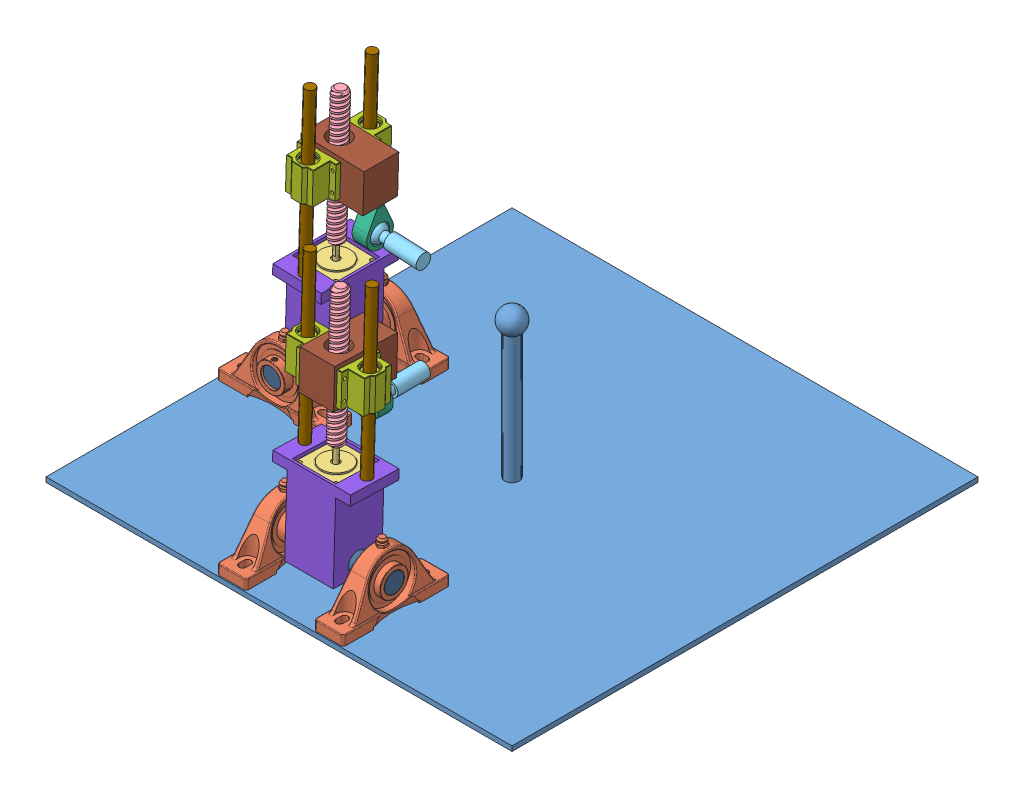
SolidWorks assembly vertical_Assem rev3, configuration Default. Lengths in mm.
Overall size (609.6 357.31 609.6).
28 component instances, 12 part files, 76 mates.
Components (placement in the parent):
- Bottom Platform rev2-1: Bottom Platform rev2 [Default] at origin size (609.6 200.03 609.6)
- 7728T560_MOUNTED BALL BEARING WITH CAST IRON HOUSING-1: 7728T560_MOUNTED BALL BEARING WITH CAST IRON HOUSING [7728T56] at (-63.5 42.8625 233.3625) x (0 0 -1) z (1 0 0) size (139.7 80.96 38.1)
- 7728T560_MOUNTED BALL BEARING WITH CAST IRON HOUSING-2: 7728T560_MOUNTED BALL BEARING WITH CAST IRON HOUSING [7728T56] at (-233.3625 42.8625 63.5) size (139.7 80.96 38.1)
- 7728T560_MOUNTED BALL BEARING WITH CAST IRON HOUSING-3: 7728T560_MOUNTED BALL BEARING WITH CAST IRON HOUSING [7728T56] at (-233.3625 42.8625 -63.5) size (139.7 80.96 38.1)
- 7728T560_MOUNTED BALL BEARING WITH CAST IRON HOUSING-4: 7728T560_MOUNTED BALL BEARING WITH CAST IRON HOUSING [7728T56] at (63.5 42.8625 233.3625) x (0 0 1) z (-1 0 0) size (139.7 80.96 38.1)
- 6627T540_POSITION-CONTROL DC MOTOR-2: 6627T540_POSITION-CONTROL DC MOTOR [6627T54] at (0 137.4326 230.4477) x (1 0 0) z (0 0.999525 -0.030807) size (57.15 58.17 99.31)
- 6627T540_POSITION-CONTROL DC MOTOR-3: 6627T540_POSITION-CONTROL DC MOTOR [6627T54] at (-230.4293 137.432 0) x (0 0 -1) z (0.031002 0.999519 0) size (57.15 58.17 99.31)
- 5966K221_BALL SCREW-3: 5966K221_BALL SCREW [5966K221] at (-229.7914 157.9961 0) x (0.970979 -0.030116 -0.237261) z (-0.031002 -0.999519 0) size (20.38 19.09 183.37)
- 5966K221_BALL SCREW-4: 5966K221_BALL SCREW [5966K221] at (0 157.9968 229.8138) x (0.271467 0.029651 0.961991) z (0 -0.999525 0.030807) size (20.38 19.09 183.37)
- top_Platform rev2-1: top_Platform rev2 [Default] at (0.7095 200.0079 0.2014) x (-0.999001 0.044698 -0.000225) z (-0.000791 -0.012664 0.999919) size (317.5 25.4 317.5) (hidden)
- ball-2: ball [Default] at (0.0499 185.85 116.2359) x (0.999641 -0.0268 0.000452) z (-0.026792 -0.999561 -0.01268) size (25.4 75.77 25.4)
- hole-1: hole [Default] at (0 258.8925 180.1999) x (0 0.030807 0.999525) z (1 0 0) size (19.05 91.29 35.03)
- ball-3: ball [Default] at (-115.947 192.5157 0.0142) x (0.040283 0.898119 -0.437904) z (0.019372 0.437476 0.899022) size (25.4 75.77 25.4)
- hole-2: hole [Default] at (-179.8387 269.1761 0) x (-0.999519 0.031002 0) z (0 0 1) size (19.05 91.29 35.03)
- 9338T100_MOUNTED LINEAR BALL BRNG-1: 9338T100_MOUNTED LINEAR BALL BRNG [9338T1] at (39.0525 243.1877 227.1881) x (0 -0.030807 -0.999525) z (0 0.999525 -0.030807) size (50.8 31.75 42.86)
- 9338T100_MOUNTED LINEAR BALL BRNG-2: 9338T100_MOUNTED LINEAR BALL BRNG [9338T1] at (-39.116 243.1887 227.2198) x (0 0.030807 0.999525) z (0 0.999525 -0.030807) size (50.8 31.75 42.86)
- 9338T100_MOUNTED LINEAR BALL BRNG-3: 9338T100_MOUNTED LINEAR BALL BRNG [9338T1] at (-226.8616 253.4814 -39.116) x (-0.999519 0.031002 0) z (0.031002 0.999519 0) size (50.8 31.75 42.86)
- 9338T100_MOUNTED LINEAR BALL BRNG-4: 9338T100_MOUNTED LINEAR BALL BRNG [9338T1] at (-226.8298 253.4804 39.0525) x (0.999519 -0.031002 0) z (0.031002 0.999519 0) size (50.8 31.75 42.86)
- motor mount-2: motor mount [Default] at (-265.5894 27.9794 -31.75) x (0 0 1) z (-0.999519 0.031002 0) size (101.6 114.3 63.5)
- motor mount-3: motor mount [Default] at (-31.75 27.9732 265.5865) x (1 0 0) z (0 0.030807 0.999525) size (101.6 114.3 63.5)
- linear bar-1: linear bar [Default] at (-230.8615 128.5512 -40.64) x (0.999519 -0.031002 0.000002) z (-0.000002 0 1) size (12.7 228.6 12.7)
- linear bar-2: linear bar [Default] at (40.64 128.5468 230.7215) x (-0.564697 -0.025425 -0.824906) z (0.825298 -0.017397 -0.564429) size (12.7 228.6 12.7)
- linear bar-3: linear bar [Default] at (-40.64 128.5516 230.8782) x (-0.912321 -0.012615 -0.409281) z (0.409475 -0.028106 -0.911888) size (12.7 228.6 12.7)
- linear bar-4: linear bar [Default] at (-230.7049 128.5463 40.64) x (0.951171 -0.029502 0.307253) z (-0.307105 0.009525 0.951628) size (12.7 228.6 12.7)
- horizontal bar-1: horizontal bar [Default] at (-79.375 42.8625 233.3625) size (158.75 25.4 25.4)
- horizontal bar-2: horizontal bar [Default] at (-233.3625 42.8625 -79.375) x (0 0 1) z (-1 0 0) size (158.75 25.4 25.4)
- screw_attach rev3-1: screw_attach rev3 [Default] at (-255.4169 228.9549 -23.241) x (0.999519 -0.031002 0) z (0 0 1) size (82.55 50.8 45.47)
- screw_attach rev3-2: screw_attach rev3 [Default] at (-23.241 218.6566 255.7704) x (0 -0.030807 -0.999525) z (1 0 0) size (82.55 50.8 45.47)
Mates (geometry in assembly coordinates):
- Coincident1: coincident anti-aligned: plane of Bottom Platform rev2-1 through (0 6.35 0) normal (0 1 0); plane of 7728T560_MOUNTED BALL BEARING WITH CAST IRON HOUSING-1 through (-44.45 6.35 203.2) normal (0 -1 0)
- Tangent3: tangent anti-aligned: cylinder of Bottom Platform rev2-1 through (-63.5 6.35 180.975) axis (0 1 0) radius 4.7625; plane of 7728T560_MOUNTED BALL BEARING WITH CAST IRON HOUSING-1 through (-58.7375 6.35 288.925) normal (-1 0 0)
- Tangent5: tangent anti-aligned: cylinder of Bottom Platform rev2-1 through (-63.5 6.35 285.75) axis (0 1 0) radius 4.7625; plane of 7728T560_MOUNTED BALL BEARING WITH CAST IRON HOUSING-1 through (-58.7375 6.35 288.925) normal (-1 0 0)
- Coincident3: coincident: cylinder of Bottom Platform rev2-1 through (-63.5 6.35 180.975) axis (0 1 0) radius 4.7625; moEndPointRef_w of 7728T560_MOUNTED BALL BEARING WITH CAST IRON HOUSING-1
- Coincident4: coincident anti-aligned: plane of Bottom Platform rev2-1 through (0 6.35 0) normal (0 1 0); plane of 7728T560_MOUNTED BALL BEARING WITH CAST IRON HOUSING-2 through (-303.2125 6.35 82.55) normal (0 -1 0)
- Coincident5: coincident anti-aligned: plane of Bottom Platform rev2-1 through (0 6.35 0) normal (0 1 0); plane of 7728T560_MOUNTED BALL BEARING WITH CAST IRON HOUSING-4 through (44.45 6.35 163.5125) normal (0 -1 0)
- Coincident6: coincident anti-aligned: plane of Bottom Platform rev2-1 through (0 6.35 0) normal (0 1 0); plane of 7728T560_MOUNTED BALL BEARING WITH CAST IRON HOUSING-3 through (-303.2125 6.35 -44.45) normal (0 -1 0)
- Tangent6: tangent anti-aligned: cylinder of Bottom Platform rev2-1 through (63.5 6.35 285.75) axis (0 1 0) radius 4.7625; plane of 7728T560_MOUNTED BALL BEARING WITH CAST IRON HOUSING-4 through (68.2625 6.35 282.575) normal (-1 0 0)
- Tangent7: tangent anti-aligned: cylinder of Bottom Platform rev2-1 through (63.5 6.35 180.975) axis (0 1 0) radius 4.7625; plane of 7728T560_MOUNTED BALL BEARING WITH CAST IRON HOUSING-4 through (68.2625 6.35 177.8) normal (-1 0 0)
- Coincident7: coincident: cylinder of Bottom Platform rev2-1 through (63.5 6.35 180.975) axis (0 1 0) radius 4.7625; moEndPointRef_w of 7728T560_MOUNTED BALL BEARING WITH CAST IRON HOUSING-4
- Tangent8: tangent anti-aligned: cylinder of Bottom Platform rev2-1 through (-180.975 6.35 63.5) axis (0 1 0) radius 4.7625; plane of 7728T560_MOUNTED BALL BEARING WITH CAST IRON HOUSING-2 through (-184.15 6.35 58.7375) normal (0 0 1)
- Tangent9: tangent anti-aligned: cylinder of Bottom Platform rev2-1 through (-285.75 6.35 63.5) axis (0 1 0) radius 4.7625; plane of 7728T560_MOUNTED BALL BEARING WITH CAST IRON HOUSING-2 through (-288.925 6.35 58.7375) normal (0 0 1)
- Coincident8: coincident: cylinder of Bottom Platform rev2-1 through (-180.975 6.35 63.5) axis (0 1 0) radius 4.7625; moEndPointRef_w of 7728T560_MOUNTED BALL BEARING WITH CAST IRON HOUSING-2
- Tangent10: tangent anti-aligned: cylinder of Bottom Platform rev2-1 through (-180.975 6.35 -63.5) axis (0 1 0) radius 4.7625; plane of 7728T560_MOUNTED BALL BEARING WITH CAST IRON HOUSING-3 through (-184.15 6.35 -68.2625) normal (0 0 1)
- Tangent11: tangent anti-aligned: cylinder of Bottom Platform rev2-1 through (-285.75 6.35 -63.5) axis (0 1 0) radius 4.7625; plane of 7728T560_MOUNTED BALL BEARING WITH CAST IRON HOUSING-3 through (-288.925 6.35 -68.2625) normal (0 0 1)
- Coincident9: coincident: cylinder of Bottom Platform rev2-1 through (-285.75 6.35 -63.5) axis (0 1 0) radius 4.7625; moEndPointRef_w of 7728T560_MOUNTED BALL BEARING WITH CAST IRON HOUSING-3
- Coincident12: coincident: moEndPointRef_w of 6627T540_POSITION-CONTROL DC MOTOR-3; plane of assembly
- Coincident13: coincident: moEndPointRef_w of 6627T540_POSITION-CONTROL DC MOTOR-2; plane of assembly
- Coincident16: coincident anti-aligned: plane of 6627T540_POSITION-CONTROL DC MOTOR-3 through (-232.9649 158.0946 0) normal (0.031002 0.999519 0); plane of 5966K221_BALL SCREW-3 through (-229.7914 157.9961 0) normal (-0.031002 -0.999519 0)
- Concentric5: concentric anti-aligned: cylinder of 6627T540_POSITION-CONTROL DC MOTOR-3 through (-229.7914 157.9961 0) axis (0.031002 0.999519 0) radius 3.175; cylinder of 5966K221_BALL SCREW-3 through (-224.2793 335.7107 0) axis (-0.031002 -0.999519 0) radius 9.525
- Concentric6: concentric anti-aligned: cylinder of 6627T540_POSITION-CONTROL DC MOTOR-2 through (0 157.9968 229.8138) axis (0 0.999525 -0.030807) radius 3.175; cylinder of 5966K221_BALL SCREW-4 through (0 335.7124 224.3363) axis (0 -0.999525 0.030807) radius 9.525
- Coincident17: coincident anti-aligned: plane of 6627T540_POSITION-CONTROL DC MOTOR-2 through (0 157.899 226.6403) normal (0 0.999525 -0.030807); plane of 5966K221_BALL SCREW-4 through (0 157.9968 229.8138) normal (0 -0.999525 0.030807)
- Concentric18: concentric anti-aligned: cylinder of top_Platform rev2-1 through (0.0162 185.3112 158.7775) axis (-0.000791 -0.012664 0.999919) radius 9.525; cylinder of ball-2 through (0.0162 185.3112 158.7775) axis (0.000791 0.012664 -0.999919) radius 9.525
- Coincident31: coincident aligned: circle of top_Platform rev2-1; circle of ball-2
- Tangent12: tangent aligned: sphere of ball-2; cylinder of hole-1 through (0 184.8557 172.9524) axis (0 0.030807 0.999525) radius 12.7
- Concentric20: concentric anti-aligned: cylinder of top_Platform rev2-1 through (-158.4494 194.4173 0.0046) axis (-0.999001 0.044698 -0.000225) radius 9.525; cylinder of ball-3 through (-158.4494 194.4173 0.0046) axis (0.999001 -0.044698 0.000225) radius 9.525
- Coincident35: coincident aligned: plane of top_Platform rev2-1 through (-159.1427 179.7207 158.5807) normal (-0.999001 0.044698 -0.000225); plane of ball-3 through (-158.4494 194.4173 0.0046) normal (-0.999001 0.044698 -0.000225)
- Tangent13: tangent aligned: sphere of ball-3; cylinder of hole-2 through (-172.6055 195.1378 0) axis (-0.999519 0.031002 0) radius 12.7
- Parallel5: parallel anti-aligned: plane of Bottom Platform rev2-1 through (0 6.35 0) normal (0 1 0); plane of top_Platform rev2-1
- Tangent16: tangent aligned: sphere of Bottom Platform rev2-1; cylinder of top_Platform rev2-1 through (-0.4257 174.6353 -0.1208) axis (0.044691 0.99892 0.012687) radius 15.875
- Tangent18: tangent aligned: sphere of Bottom Platform rev2-1; plane of top_Platform rev2-1 through (0.7095 200.0079 0.2014) normal (0.044691 0.99892 0.012687)
- Coincident50: coincident anti-aligned: plane of 6627T540_POSITION-CONTROL DC MOTOR-3 through (-217.79 58.2621 25.019) normal (-0.031002 -0.999519 0); plane of motor mount-2 through (-264.6051 59.7142 -31.75) normal (0.031002 0.999519 0)
- Coincident51: coincident anti-aligned: plane of 6627T540_POSITION-CONTROL DC MOTOR-3 through (-205.199 131.567 -28.575) normal (0 0 -1); plane of motor mount-2 through (-258.8724 142.1261 -28.575) normal (0 0 1)
- Coincident52: coincident anti-aligned: plane of 6627T540_POSITION-CONTROL DC MOTOR-3 through (-259.148 133.2403 -25.4) normal (-0.999519 0.031002 0); plane of motor mount-2 through (-258.8724 142.1261 -28.575) normal (0.999519 -0.031002 0)
- Coincident53: coincident anti-aligned: plane of 6627T540_POSITION-CONTROL DC MOTOR-2 through (-25.019 59.1948 247.9539) normal (0 -0.999525 0.030807); plane of motor mount-3 through (-31.75 59.7081 264.6084) normal (0 0.999525 -0.030807)
- Coincident54: coincident anti-aligned: plane of 6627T540_POSITION-CONTROL DC MOTOR-2 through (25.4 131.4747 202.0427) normal (0 -0.030807 -0.999525); plane of motor mount-3 through (-28.575 140.3605 201.7688) normal (0 0.030807 0.999525)
- Coincident55: coincident anti-aligned: plane of 6627T540_POSITION-CONTROL DC MOTOR-2 through (28.575 133.1375 255.9921) normal (1 0 0); plane of motor mount-3 through (28.575 142.1211 258.8917) normal (-1 0 0)
- Coincident56: coincident aligned: plane of motor mount-2 through (-262.4396 129.5306 -50.8) normal (-0.031002 -0.999519 0); plane of linear bar-1 through (-230.8615 128.5512 -40.64) normal (-0.031002 -0.999519 0)
- Concentric43: concentric anti-aligned: cylinder of motor mount-2 through (-230.4678 141.245 -40.64) axis (0.031002 0.999519 0) radius 6.35; cylinder of linear bar-1 through (-223.7745 357.0413 -40.64) axis (-0.031002 -0.999519 0) radius 6.35
- Concentric44: concentric anti-aligned: cylinder of motor mount-2 through (-230.3112 141.2402 40.64) axis (0.031002 0.999519 0) radius 6.35; cylinder of linear bar-4 through (-223.6179 357.0364 40.64) axis (-0.031002 -0.999519 0) radius 6.35
- Coincident57: coincident aligned: plane of motor mount-2 through (-262.4396 129.5306 50.8) normal (-0.031002 -0.999519 0); plane of linear bar-4 through (-230.7049 128.5463 40.64) normal (-0.031002 -0.999519 0)
- Concentric45: concentric anti-aligned: cylinder of motor mount-3 through (-40.64 141.2456 230.4869) axis (0 0.999525 -0.030807) radius 6.35; cylinder of linear bar-3 through (-40.64 357.0431 223.8356) axis (0 -0.999525 0.030807) radius 6.35
- Concentric46: concentric anti-aligned: cylinder of motor mount-3 through (40.64 141.2408 230.3303) axis (0 0.999525 -0.030807) radius 6.35; cylinder of linear bar-2 through (40.64 357.0383 223.679) axis (0 -0.999525 0.030807) radius 6.35
- Coincident58: coincident aligned: plane of motor mount-3 through (-50.8 129.5249 262.4565) normal (0 -0.999525 0.030807); plane of linear bar-3 through (-40.64 128.5516 230.8782) normal (0 -0.999525 0.030807)
- Coincident59: coincident aligned: plane of motor mount-3 through (50.8 129.5249 262.4565) normal (0 -0.999525 0.030807); plane of linear bar-2 through (40.64 128.5468 230.7215) normal (0 -0.999525 0.030807)
- Concentric47: concentric anti-aligned: cylinder of 9338T100_MOUNTED LINEAR BALL BRNG-1 through (40.64 221.7666 227.8483) axis (0 0.999525 -0.030807) radius 6.35; cylinder of linear bar-2 through (40.64 357.0383 223.679) axis (0 -0.999525 0.030807) radius 6.35
- Concentric48: concentric anti-aligned: cylinder of 9338T100_MOUNTED LINEAR BALL BRNG-4 through (-227.4943 232.0594 40.64) axis (0.031002 0.999519 0) radius 6.35; cylinder of linear bar-4 through (-223.6179 357.0364 40.64) axis (-0.031002 -0.999519 0) radius 6.35
- Coincident60: coincident aligned: plane of 7728T560_MOUNTED BALL BEARING WITH CAST IRON HOUSING-1 through (-79.375 42.8625 233.3625) normal (-1 0 0); plane of horizontal bar-1 through (-79.375 42.8625 233.3625) normal (-1 0 0)
- Concentric51: concentric anti-aligned: cylinder of 7728T560_MOUNTED BALL BEARING WITH CAST IRON HOUSING-1 through (-79.375 42.8625 233.3625) axis (1 0 0) radius 12.7025; cylinder of horizontal bar-1 through (79.375 42.8625 233.3625) axis (-1 0 0) radius 12.7
- Coincident61: coincident aligned: plane of 7728T560_MOUNTED BALL BEARING WITH CAST IRON HOUSING-3 through (-233.3625 42.8625 -79.375) normal (0 0 -1); plane of horizontal bar-2 through (-233.3625 42.8625 -79.375) normal (0 0 -1)
- Concentric52: concentric anti-aligned: cylinder of 7728T560_MOUNTED BALL BEARING WITH CAST IRON HOUSING-3 through (-233.3625 42.8625 -79.375) axis (0 0 1) radius 12.7025; cylinder of horizontal bar-2 through (-233.3625 42.8625 79.375) axis (0 0 -1) radius 12.7
- Concentric54: concentric anti-aligned: cylinder of motor mount-2 through (-233.3625 42.8625 31.75) axis (0 0 1) radius 12.7; cylinder of horizontal bar-2 through (-233.3625 42.8625 79.375) axis (0 0 -1) radius 12.7
- Concentric56: concentric anti-aligned: cylinder of motor mount-3 through (31.75 42.8625 233.3625) axis (1 0 0) radius 12.7; cylinder of horizontal bar-1 through (79.375 42.8625 233.3625) axis (-1 0 0) radius 12.7
- Screw1: screw = 25.4 mm anti-aligned: cylinder of 5966K221_BALL SCREW-3 through (-224.2793 335.7107 0) axis (-0.031002 -0.999519 0) radius 9.525; cylinder of screw_attach rev3-1 through (-227.6173 228.0926 0) axis (0.031002 0.999519 0) radius 14
- Coincident62: coincident anti-aligned: plane of 9338T100_MOUNTED LINEAR BALL BRNG-3 through (-200.8094 274.1149 -23.241) normal (0 0 1); plane of screw_attach rev3-1 through (-255.4169 228.9549 -23.241) normal (0 0 -1)
- Concentric59: concentric anti-aligned: cylinder of 9338T100_MOUNTED LINEAR BALL BRNG-3 through (-205.0469 265.5109 -35.2037) axis (0 0 1) radius 1.9844; cylinder of screw_attach rev3-1 through (-205.0469 265.5109 -23.241) axis (0 0 -1) radius 1.9844
- Concentric60: concentric anti-aligned: cylinder of 9338T100_MOUNTED LINEAR BALL BRNG-3 through (-247.8888 266.8397 -35.2037) axis (0 0 1) radius 1.9844; cylinder of screw_attach rev3-1 through (-247.8888 266.8397 -23.241) axis (0 0 -1) radius 1.9844
- Parallel10: parallel aligned: plane of motor mount-2 through (-264.6051 59.7142 -31.75) normal (-0.999519 0.031002 0); plane of screw_attach rev3-1 through (-255.4169 228.9549 22.225) normal (-0.999519 0.031002 0)
- Parallel12: parallel anti-aligned: plane of 9338T100_MOUNTED LINEAR BALL BRNG-4 through (-251.5532 275.6888 23.1775) normal (0 0 -1); plane of screw_attach rev3-1 through (-255.4169 228.9549 22.225) normal (0 0 1)
- Screw2: screw = 25.4 mm anti-aligned: cylinder of 5966K221_BALL SCREW-4 through (0 335.7124 224.3363) axis (0 -0.999525 0.030807) radius 9.525; cylinder of screw_attach rev3-2 through (0 217.7997 227.9706) axis (0 0.999525 -0.030807) radius 14
- Parallel15: parallel aligned: plane of motor mount-3 through (-31.75 59.7081 264.6084) normal (0 0.030807 0.999525); plane of screw_attach rev3-2 through (22.225 218.6566 255.7704) normal (0 0.030807 0.999525)
- Parallel19: parallel anti-aligned: plane of 9338T100_MOUNTED LINEAR BALL BRNG-1 through (23.1775 263.8262 201.1399) normal (-1 0 0); plane of screw_attach rev3-2 through (22.225 218.6566 255.7704) normal (1 0 0)
- Parallel21: parallel aligned: plane of hole-1 through (0 185.4425 191.9933) normal (0 0.030807 0.999525); plane of motor mount-3 through (-31.75 59.7081 264.6084) normal (0 0.030807 0.999525)
- Tangent24: tangent aligned: sphere of ball-2; plane of hole-1 through (0 185.4425 191.9933) normal (0 0.030807 0.999525)
- Concentric78: concentric anti-aligned: cylinder of hole-2 through (-181.1576 226.6516 0) axis (0.031002 0.999519 0) radius 4.7625; cylinder of screw_attach rev3-1 through (-181.1576 226.6516 0) axis (-0.031002 -0.999519 0) radius 4.2164
- Coincident76: coincident anti-aligned: plane of hole-2 through (-171.6372 226.3563 4.7625) normal (0.031002 0.999519 0); plane of screw_attach rev3-1 through (-172.9066 226.3957 22.225) normal (-0.031002 -0.999519 0)
- Parallel22: parallel aligned: plane of hole-2 through (-191.6463 195.7284 0) normal (-0.999519 0.031002 0); plane of motor mount-2 through (-264.6051 59.7142 -31.75) normal (-0.999519 0.031002 0)
- Tangent25: tangent aligned: sphere of ball-3; plane of hole-2 through (-191.6463 195.7284 0) normal (-0.999519 0.031002 0)
- Concentric79: concentric anti-aligned: cylinder of hole-1 through (0 216.3677 181.5106) axis (0 0.999525 -0.030807) radius 4.7625; cylinder of screw_attach rev3-2 through (0 216.3677 181.5106) axis (0 -0.999525 0.030807) radius 4.2164
- Coincident78: coincident anti-aligned: plane of hole-1 through (4.7625 216.0743 171.9902) normal (0 0.999525 -0.030807); plane of screw_attach rev3-2 through (22.225 216.1134 173.2596) normal (0 -0.999525 0.030807)
- Concentric84: concentric anti-aligned: cylinder of 9338T100_MOUNTED LINEAR BALL BRNG-2 through (-35.2037 256.5429 248.2496) axis (1 0 0) radius 1.9844; cylinder of screw_attach rev3-2 through (-23.241 256.5429 248.2496) axis (-1 0 0) radius 1.9844
- Concentric85: concentric anti-aligned: cylinder of 9338T100_MOUNTED LINEAR BALL BRNG-2 through (-35.2037 231.1549 249.0321) axis (1 0 0) radius 1.9844; cylinder of screw_attach rev3-2 through (-23.241 231.1549 249.0321) axis (-1 0 0) radius 1.9844
- Coincident79: coincident anti-aligned: plane of 9338T100_MOUNTED LINEAR BALL BRNG-2 through (-23.241 263.8272 201.1716) normal (1 0 0); plane of screw_attach rev3-2 through (-23.241 218.6566 255.7704) normal (-1 0 0)
- Coincident80: coincident aligned: plane of 9338T100_MOUNTED LINEAR BALL BRNG-1 through (29.5275 265.3913 251.9158) normal (0 0.999525 -0.030807); plane of 9338T100_MOUNTED LINEAR BALL BRNG-2 through (-29.591 263.8272 201.1716) normal (0 0.999525 -0.030807)
- Coincident81: coincident aligned: plane of 9338T100_MOUNTED LINEAR BALL BRNG-3 through (-200.8094 274.1149 -29.591) normal (0.031002 0.999519 0); plane of 9338T100_MOUNTED LINEAR BALL BRNG-4 through (-251.5532 275.6888 29.5275) normal (0.031002 0.999519 0)
- LimitDistance1: limit distance = 76.5953 mm anti-aligned: plane of motor mount-3 through (-31.75 142.2189 262.0652) normal (0 0.999525 -0.030807); plane of screw_attach rev3-2 through (22.225 216.1134 173.2596) normal (0 -0.999525 0.030807)
